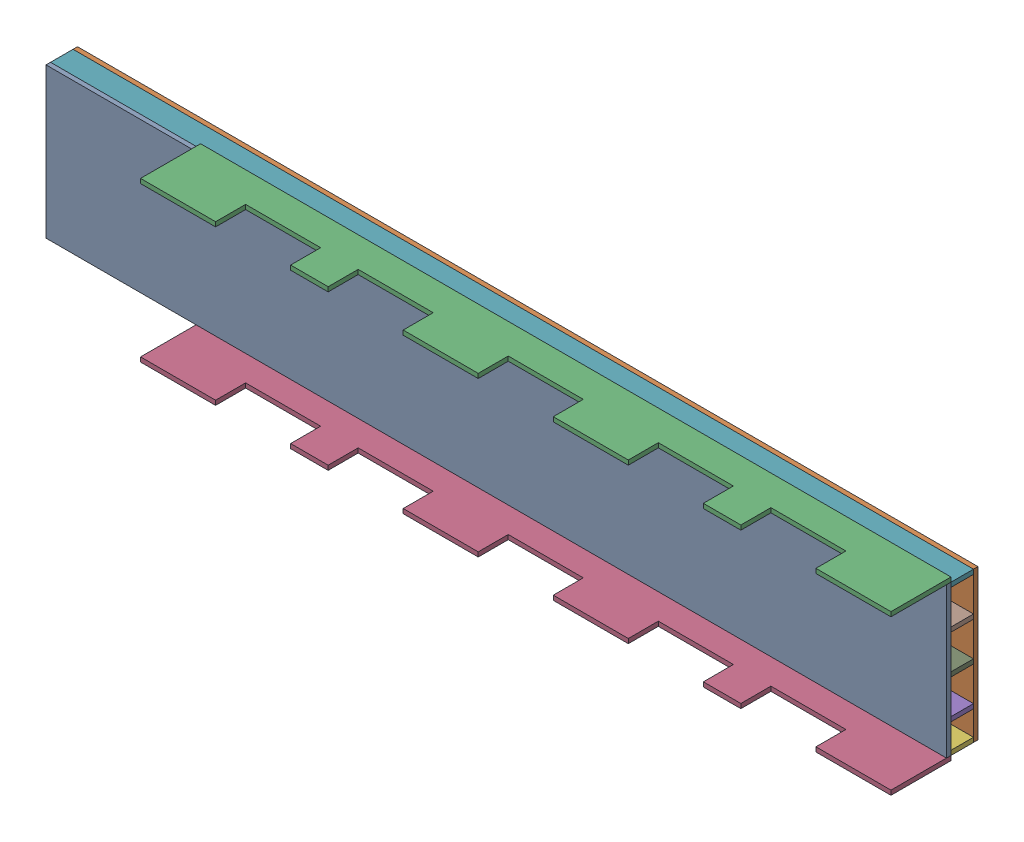
SolidWorks assembly assembly, configuration Default. Lengths in mm.
Overall size (600 106 58).
9 component instances, 4 part files, 24 mates.
Components (placement in the parent):
- deck-1: deck [Default] at (-59.2989 385.3404 560.9549) size (600 100 3)
- below-deck-1: below-deck [Default] at (-59.2989 385.3404 542.9549) size (600 100 3)
- guard-1: guard [Default] at (40.7011 488.3404 560.9549) x (1 0 0) z (0 -1 0) size (500 40 3)
- guard-2: guard [Default] at (40.7011 385.3404 560.9549) x (1 0 0) z (0 -1 0) size (500 40 3)
- support-1: support [Default] at (-59.2989 407.7604 545.9549) x (1 0 0) z (0 -1 0) size (600 15 3)
- support-2: support [Default] at (-59.2989 385.3404 560.9549) x (1 0 0) z (0 1 0) size (600 15 3)
- support-3: support [Default] at (-59.2989 482.3404 560.9549) x (1 0 0) z (0 1 0) size (600 15 3)
- support-4: support [Default] at (-59.2989 459.4804 545.9549) x (1 0 0) z (0 -1 0) size (600 15 3)
- support-5: support [Default] at (-59.2989 433.6204 545.9549) x (1 0 0) z (0 -1 0) size (600 15 3)
Mates (geometry in assembly coordinates):
- Coincident2: coincident anti-aligned: plane of deck-1 through (-59.2989 385.3404 560.9549) normal (0 0 -1); plane of support-2 through (-59.2989 388.3404 560.9549) normal (0 0 1)
- Coincident3: coincident aligned: line of deck-1 through (-59.2989 385.3404 560.9549) axis (1 0 0); line of support-2 through (-59.2989 385.3404 560.9549) axis (1 0 0)
- Coincident6: coincident anti-aligned: line of deck-1 through (540.7011 385.3404 560.9549) axis (0 1 0); line of support-2 through (540.7011 388.3404 560.9549) axis (0 -1 0)
- Coincident9: coincident anti-aligned: plane of deck-1 through (-59.2989 385.3404 560.9549) normal (0 0 -1); plane of support-3 through (-59.2989 485.3404 560.9549) normal (0 0 1)
- Coincident10: coincident anti-aligned: line of deck-1 through (540.7011 485.3404 560.9549) axis (-1 0 0); line of support-3 through (-59.2989 485.3404 560.9549) axis (1 0 0)
- Coincident11: coincident anti-aligned: line of deck-1 through (540.7011 385.3404 560.9549) axis (0 1 0); line of support-3 through (540.7011 485.3404 560.9549) axis (0 -1 0)
- Coincident12: coincident: plane of deck-1 through (-59.2989 385.3404 560.9549) normal (0 0 -1); plane of support-5 through (-59.2989 435.996 560.9549) normal (0 0 1)
- Coincident13: coincident: line of deck-1 through (540.7011 385.3404 560.9549) axis (0 1 0); line of support-5 through (540.7011 435.996 560.9549) axis (0 1 0)
- Coincident14: coincident: plane of deck-1 through (-59.2989 385.3404 560.9549) normal (0 0 -1); plane of support-4 through (-59.2989 462.1588 560.9549) normal (0 0 1)
- Coincident15: coincident: line of deck-1 through (540.7011 385.3404 560.9549) axis (0 1 0); line of support-4 through (540.7011 462.1588 560.9549) axis (0 1 0)
- Coincident16: coincident: plane of deck-1 through (-59.2989 385.3404 560.9549) normal (0 0 -1); plane of support-1 through (-59.2989 409.8262 560.9549) normal (0 0 1)
- Coincident17: coincident: line of deck-1 through (540.7011 385.3404 560.9549) axis (0 1 0); line of support-1 through (540.7011 409.8262 560.9549) axis (0 1 0)
- Coincident20: coincident aligned: line of below deck-1 through (540.7011 485.3404 545.9549) axis (-1 0 0); line of support-3 through (540.7011 485.3404 545.9549) axis (-1 0 0)
- Coincident21: coincident anti-aligned: line of below deck-1 through (-59.2989 385.3404 545.9549) axis (1 0 0); line of support-2 through (540.7011 385.3404 545.9549) axis (-1 0 0)
- Coincident22: coincident aligned: line of below deck-1 through (-59.2989 485.3404 545.9549) axis (0 -1 0); line of support-3 through (-59.2989 485.3404 545.9549) axis (0 -1 0)
- Coincident23: coincident anti-aligned: plane of deck-1 through (-59.2989 485.3404 563.9549) normal (0 1 0); plane of guard-1 through (40.7011 485.3404 560.9549) normal (0 -1 0)
- Coincident24: coincident aligned: line of guard-1 through (40.7011 485.3404 560.9549) axis (1 0 0); line of support-3 through (-59.2989 485.3404 560.9549) axis (1 0 0)
- Coincident25: coincident anti-aligned: line of deck-1 through (540.7011 485.3404 563.9549) axis (0 0 -1); line of guard-1 through (540.7011 485.3404 560.9549) axis (0 0 1)
- Coincident26: coincident anti-aligned: plane of deck-1 through (-59.2989 385.3404 563.9549) normal (0 -1 0); plane of guard-2 through (40.7011 385.3404 560.9549) normal (0 1 0)
- Coincident28: coincident aligned: line of guard-2 through (40.7011 385.3404 560.9549) axis (1 0 0); line of support-2 through (-59.2989 385.3404 560.9549) axis (1 0 0)
- Coincident29: coincident anti-aligned: line of deck-1 through (540.7011 385.3404 563.9549) axis (0 0 -1); line of guard-2 through (540.7011 385.3404 560.9549) axis (0 0 1)
- Distance1: distance = 22.86 mm: point of support-4; moEndPointRef_w of support-3
- Distance2: distance = 22.86 mm: line of support-4 through (-59.2989 456.4804 560.9549) axis (0 0 -1); line of support-5 through (-59.2989 433.6204 560.9549) axis (0 0 -1)
- Distance3: distance = 22.86 mm: line of support-1 through (-59.2989 407.7604 560.9549) axis (0 0 -1); line of support-5 through (-59.2989 430.6204 560.9549) axis (0 0 -1)
